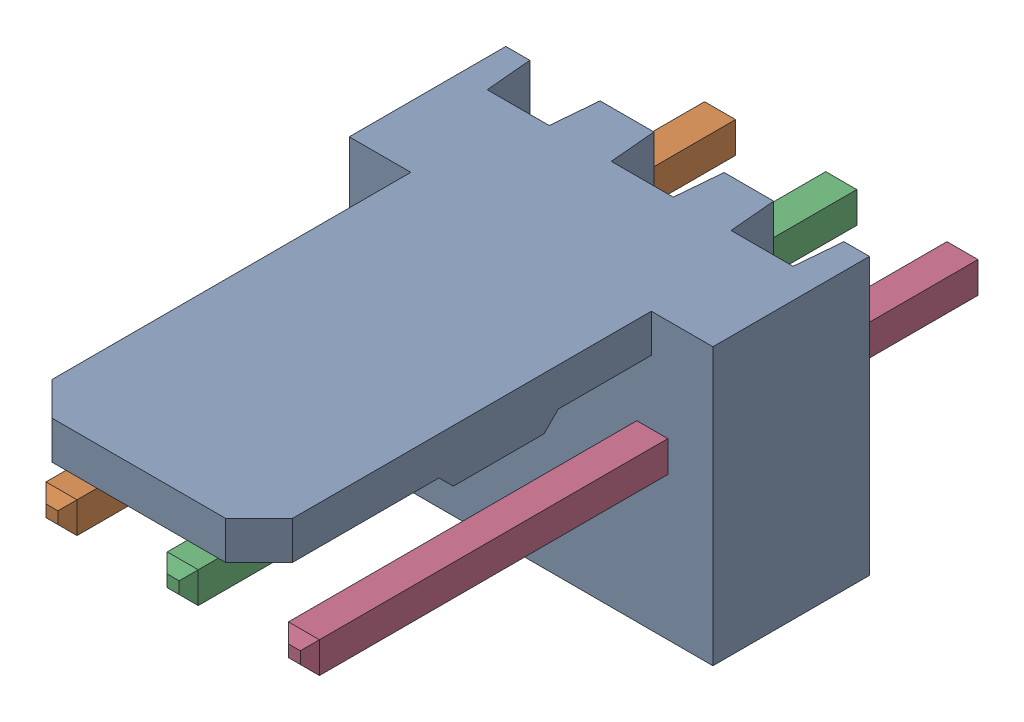
SolidWorks assembly Molex PCB 3 pin v2 v6_4, configuration Default. Lengths in mm.
Overall size (7.62 5.79 14.92).
4 component instances, 2 part files, 0 mates.
Components (placement in the parent):
- BASE9710016 (1)-1: BASE9710016 (1) [Default] at (2.54 2.895 -8.22) size (7.62 5.79 11.5)
- PINO9710016 (1)-1: PINO9710016 (1) [Default] at (1.27 3.325 -0.72) size (0.65 0.65 14.2)
- PINO9710016 (1)-2: PINO9710016 (1) [Default] at (3.81 3.325 -0.72) size (0.65 0.65 14.2)
- PINO9710016 (1)-3: PINO9710016 (1) [Default] at (6.35 3.325 -0.72) size (0.65 0.65 14.2)
